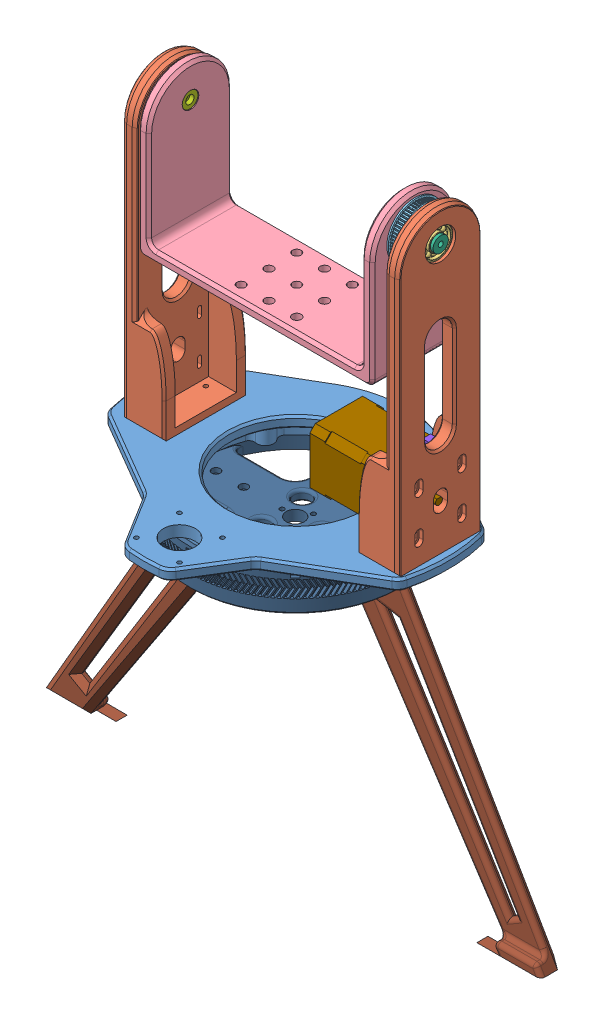
SolidWorks assembly RF_DUT_Positioner, configuration Default. Lengths in mm.
Overall size (360.07 461.68 190.1).
16 component instances, 11 part files, 0 mates.
Components (placement in the parent):
- updated_Pan_mount-1: updated_Pan_mount [Default] x (1 0 0) z (0 -1 0) size (220 190.1 21.85)
- side_support-1: side_support [Default] at (89 8 0) size (30.1 220 60.2)
- side_support-2: side_support [Default] at (-80 8 0) x (-1 0 0) z (0 0 -1) size (30.1 220 60.2)
- Ball_Bearing_608zz-1: Ball_Bearing_608zz [Default] at (98.5331 195.9592 0.109) x (0.00416 0.004207 -0.999982) z (0.999985 0.003614 0.004176) size (22 22 7.01)
- Ball_Bearing_608zz-2: Ball_Bearing_608zz [Default] at (-89.5472 196.0329 0.0212) x (0 0 -1) z (1 0 0) size (22 22 7.01)
- DUT_Bridge-1: DUT_Bridge [Default] at (0.5 111 0) size (170.5 108 60)
- Pulley_GT2_generated_60t-1: Pulley_GT2_generated_60t [Default] at (92.5 195.7821 0.1085) x (0 -1 0) z (-1 0 0) size (40 40 9.5)
- bearing_cap-1: bearing_cap [Default] at (-94.9901 195.9968 0.0395) size (3 11 11)
- non_gear_spacer-1: non_gear_spacer [Default] at (-76.4514 195.9919 0.0295) x (-1 0 0) z (0 0 -1) size (15.5 11.6 11.6)
- bearing_cap-2: bearing_cap [Default] at (104.1437 196.0338 -0.0455) x (-1 0 0) z (0 0 -1) size (3 11 11)
- non_gear_spacer-2: non_gear_spacer [Default] at (83.5061 195.803 0.1408) size (15.5 11.6 11.6)
- Stepper_Spacer-1: Stepper_Spacer [Default] at (78.9105 35.1888 -0.0098) x (0 0 -1) z (1 0 0) size (42 42 20)
- Nema 17 Stepper Motor 17HD48002H-22B-1: Nema 17 Stepper Motor 17HD48002H-22B [Défaut] at (41.8414 35.1465 -0.0858) x (0 0 1) z (-1 0 0) size (42 54.3 72)
- 144tooth_base_mount-1: 144tooth_base_mount [Default] at (0.1598 -22.9327 0.7369) x (1 0 0) z (0 1 0) size (152.17 152.17 27)
- support_leg-1: support_leg [Default] at (88.846 -104.7401 -12.2802) x (0.5 -0.866025 0) z (-0.866025 -0.5 0) size (245.44 16 40)
- support_leg-2: support_leg [Default] at (-88.846 -104.7401 3.7198) x (-0.5 -0.866025 0) z (0.866025 -0.5 0) size (245.44 16 40)
